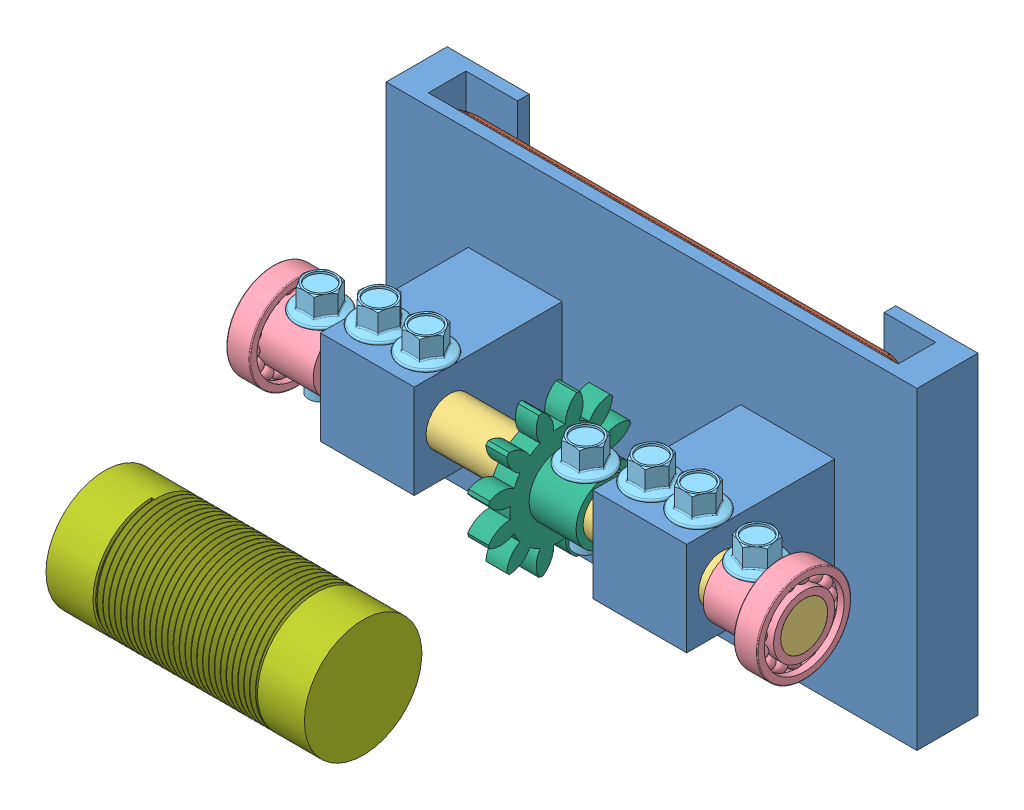
SolidWorks assembly Assem2, configuration Default. Lengths in mm.
Overall size (297.05 208.33 104.25).
14 component instances, 7 part files, 28 mates.
Components (placement in the parent):
- panpart1-1: panpart1 [Default] at (50.4862 130.7622 195.8282) size (226 133.5 89)
- tablet-1: tablet [Default] at (50.8522 130.6632 215.8282) size (200.66 129.98 23.56)
- shaft-1: shaft [Default] at (-62.5138 130.7622 269.8282) x (1 0 0) z (0 0 -1) size (226 20 20)
- Bearing-1: Bearing [Default] at (-1.8143 116.4662 250.1482) size (30 40 40)
- Bearing-2: Bearing [Default] at (102.7866 145.0582 250.1482) x (-1 0 0) z (0 0 1) size (30 40 40)
- hex flange machine screw_am-1: hex flange machine screw_am [B18.6.7M - M10 x 1.5 x 30 Indented HFMS --30N] at (-42.5138 154.4622 269.8282) x (0 -1 0) z (0 0 1) size (40.7 21 21)
- hex flange machine screw_am-2: hex flange machine screw_am [B18.6.7M - M10 x 1.5 x 30 Indented HFMS --30N] at (143.4862 154.4622 269.8282) x (0 -1 0) z (-0.357498 0 0.933914) size (40.7 21 21)
- hex flange machine screw_am-3: hex flange machine screw_am [B18.6.7M - M10 x 1.5 x 30 Indented HFMS --30N] at (-17.5138 161.4622 269.8282) x (0 -1 0) z (-0.737651 0 0.675182) size (40.7 21 21)
- hex flange machine screw_am-4: hex flange machine screw_am [B18.6.7M - M10 x 1.5 x 30 Indented HFMS --30N] at (2.4862 161.4622 269.8282) x (0 -1 0) z (0 0 1) size (40.7 21 21)
- hex flange machine screw_am-5: hex flange machine screw_am [B18.6.7M - M10 x 1.5 x 30 Indented HFMS --30N] at (98.4862 161.4622 269.8282) x (0 -1 0) z (0 0 1) size (40.7 21 21)
- hex flange machine screw_am-6: hex flange machine screw_am [B18.6.7M - M10 x 1.5 x 30 Indented HFMS --30N] at (118.4862 161.4622 269.8282) x (0 -1 0) z (0 0 1) size (40.7 21 21)
- Gear-1: Gear [Default] at (321.6356 216.6863 318.7793) x (1 0 0) z (0 0 -1) size (28.89 60.5 60.5)
- hex flange machine screw_am-8: hex flange machine screw_am [B18.6.7M - M10 x 1.5 x 30 Indented HFMS --30N] at (70.4862 154.4622 269.8282) x (0 -1 0) z (0 0 1) size (40.7 21 21)
- worm-1: worm [Default] at (-113.563 14.8313 270.5485) size (110 50 52.57)
Mates (geometry in assembly coordinates):
- Coincident1: coincident anti-aligned: plane of panpart1-1 through (150.4862 194.2622 216.8282) normal (0 0 -1); plane of tablet-1 through (50.8522 130.6632 216.8282) normal (0 0 1)
- Coincident3: coincident: plane of panpart1-1 through (163.4862 70.7622 221.8282) normal (0 1 0); line of tablet-1 through (-38.9415 70.7622 214.8168) axis (1 0 0)
- Concentric1: concentric anti-aligned: cylinder of shaft-1 through (163.4862 130.7622 269.8282) axis (-1 0 0) radius 10; cylinder of panpart1-1 through (-96.5138 130.7622 269.8282) axis (1 0 0) radius 10
- Concentric2: concentric anti-aligned: cylinder of shaft-1 through (163.4862 130.7622 269.8282) axis (-1 0 0) radius 10; cylinder of panpart1-1 through (-96.5138 130.7622 269.8282) axis (1 0 0) radius 10
- Concentric3: concentric anti-aligned: cylinder of shaft-1 through (163.4862 130.7622 269.8282) axis (-1 0 0) radius 10; cylinder of Bearing-1 through (-122.5138 130.7622 269.8276) axis (1 0 0) radius 10
- Concentric4: concentric aligned: cylinder of shaft-1 through (163.4862 130.7622 269.8282) axis (-1 0 0) radius 10; cylinder of Bearing-2 through (223.4862 130.7622 269.8276) axis (-1 0 0) radius 10
- Concentric5: concentric anti-aligned: cylinder of hex flange machine screw_am-1 through (-42.5138 179.8622 269.8282) axis (0 1 0) radius 5; cylinder of Bearing-1 through (-42.5138 150.7622 269.8282) axis (0 -1 0) radius 5
- Concentric6: concentric anti-aligned: cylinder of hex flange machine screw_am-1 through (-42.5138 179.8622 269.8282) axis (0 1 0) radius 5; cylinder of shaft-1 through (-42.5138 140.7622 269.8282) axis (0 -1 0) radius 5
- Tangent1: tangent anti-aligned: plane of hex flange machine screw_am-1 through (-37.5138 143.7622 269.8282) normal (0 -1 0); cylinder of Bearing-1 through (-122.5138 130.7622 269.8276) axis (1 0 0) radius 13
- Concentric7: concentric aligned: cylinder of hex flange machine screw_am-2 through (143.4862 179.8622 269.8282) axis (0 1 0) radius 5; cylinder of Bearing-2 through (143.4862 110.7622 269.8282) axis (0 1 0) radius 5
- Concentric8: concentric anti-aligned: cylinder of hex flange machine screw_am-2 through (143.4862 179.8622 269.8282) axis (0 1 0) radius 5; cylinder of shaft-1 through (143.4862 140.7622 269.8282) axis (0 -1 0) radius 5
- Tangent2: tangent anti-aligned: cylinder of Bearing-2 through (223.4862 130.7622 269.8276) axis (-1 0 0) radius 13; plane of hex flange machine screw_am-2 through (148.1557 143.7622 271.6157) normal (0 -1 0)
- Concentric9: concentric anti-aligned: cylinder of hex flange machine screw_am-3 through (-17.5138 186.8622 269.8282) axis (0 1 0) radius 5; cylinder of shaft-1 through (-17.5138 140.7622 269.8282) axis (0 -1 0) radius 5
- Concentric10: concentric aligned: cylinder of hex flange machine screw_am-3 through (-17.5138 186.8622 269.8282) axis (0 1 0) radius 5; cylinder of panpart1-1 through (-17.5138 60.7622 269.8282) axis (0 1 0) radius 5
- Concentric11: concentric anti-aligned: cylinder of hex flange machine screw_am-4 through (2.4862 186.8622 269.8282) axis (0 1 0) radius 5; cylinder of shaft-1 through (2.4862 140.7622 269.8282) axis (0 -1 0) radius 5
- Concentric12: concentric aligned: cylinder of hex flange machine screw_am-4 through (2.4862 186.8622 269.8282) axis (0 1 0) radius 5; cylinder of panpart1-1 through (2.4862 60.7622 269.8282) axis (0 1 0) radius 5
- Concentric13: concentric anti-aligned: cylinder of hex flange machine screw_am-5 through (98.4862 186.8622 269.8282) axis (0 1 0) radius 5; cylinder of shaft-1 through (98.4862 140.7622 269.8282) axis (0 -1 0) radius 5
- Concentric15: concentric aligned: cylinder of hex flange machine screw_am-5 through (98.4862 186.8622 269.8282) axis (0 1 0) radius 5; cylinder of panpart1-1 through (98.4862 60.7622 269.8282) axis (0 1 0) radius 5
- Concentric16: concentric anti-aligned: cylinder of hex flange machine screw_am-6 through (118.4862 186.8622 269.8282) axis (0 1 0) radius 5; cylinder of shaft-1 through (118.4862 140.7622 269.8282) axis (0 -1 0) radius 5
- Concentric17: concentric aligned: cylinder of hex flange machine screw_am-6 through (118.4862 186.8622 269.8282) axis (0 1 0) radius 5; cylinder of panpart1-1 through (118.4862 60.7622 269.8282) axis (0 1 0) radius 5
- Coincident5: coincident anti-aligned: plane of panpart1-1 through (-27.5138 150.7622 284.8282) normal (0 1 0); plane of hex flange machine screw_am-3 through (-14.1379 150.7622 273.5165) normal (0 -1 0)
- Coincident6: coincident anti-aligned: plane of panpart1-1 through (-27.5138 150.7622 284.8282) normal (0 1 0); plane of hex flange machine screw_am-4 through (7.4862 150.7622 269.8282) normal (0 -1 0)
- Coincident7: coincident anti-aligned: plane of panpart1-1 through (128.4862 150.7622 284.8282) normal (0 1 0); plane of hex flange machine screw_am-6 through (123.4862 150.7622 269.8282) normal (0 -1 0)
- Coincident8: coincident anti-aligned: plane of panpart1-1 through (128.4862 150.7622 284.8282) normal (0 1 0); plane of hex flange machine screw_am-5 through (103.4862 150.7622 269.8282) normal (0 -1 0)
- Concentric19: concentric anti-aligned: cylinder of shaft-1 through (163.4862 130.7622 269.8282) axis (-1 0 0) radius 10; cylinder of Gear-1 through (50.4862 130.7622 269.8282) axis (1 0 0) radius 10
- Concentric21: concentric anti-aligned: cylinder of hex flange machine screw_am-8 through (70.4862 179.8622 269.8282) axis (0 1 0) radius 5; cylinder of shaft-1 through (70.4862 140.7622 269.8282) axis (0 -1 0) radius 5
- Concentric22: concentric aligned: cylinder of hex flange machine screw_am-8 through (70.4862 179.8622 269.8282) axis (0 1 0) radius 5; cylinder of Gear-1 through (70.4862 100.5126 269.8282) axis (0 1 0) radius 5
- Tangent3: tangent anti-aligned: cylinder of Gear-1 through (79.3762 130.7622 269.8282) axis (-1 0 0) radius 13; plane of hex flange machine screw_am-8 through (75.4862 143.7622 269.8282) normal (0 -1 0)
